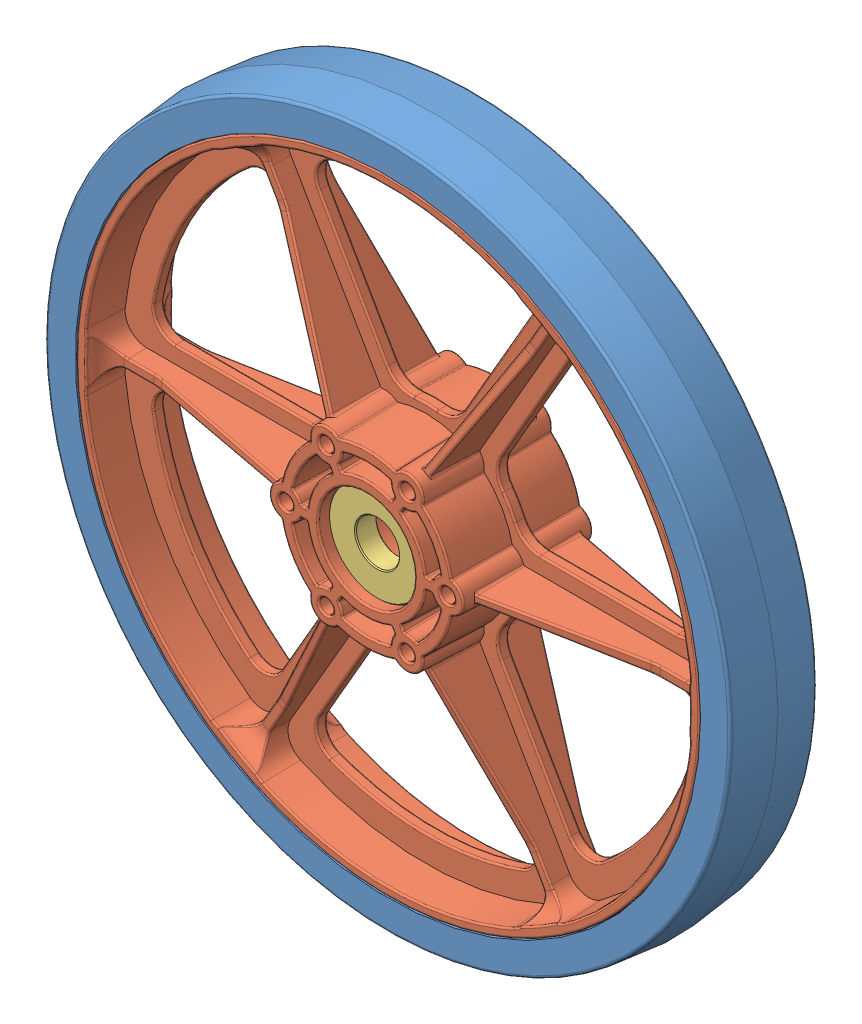
SolidWorks assembly 8inWheel_AndyMarkAlternative, configuration Default. Lengths in mm.
Overall size (204.35 204.35 38.11).
4 component instances, 3 part files, 0 mates.
Components (placement in the parent):
- 2010 8 tread-1: 2010 8 tread [Default] at (0 0 12.7) size (204.35 204.35 25.4)
- 2010 8 hub-1: 2010 8 hub [Default] at origin size (190.5 190.5 38.11)
- r8 bearing-1: r8 bearing [Default] at (0 0 -3.0988) x (-0.726935 0.686706 0) z (0 0 1) size (28.57 28.57 6.35)
- r8 bearing-2: r8 bearing [Default] at (0 0 28.575) x (0.399336 0.916804 0) z (0 0 -1) size (28.57 28.57 6.35)
